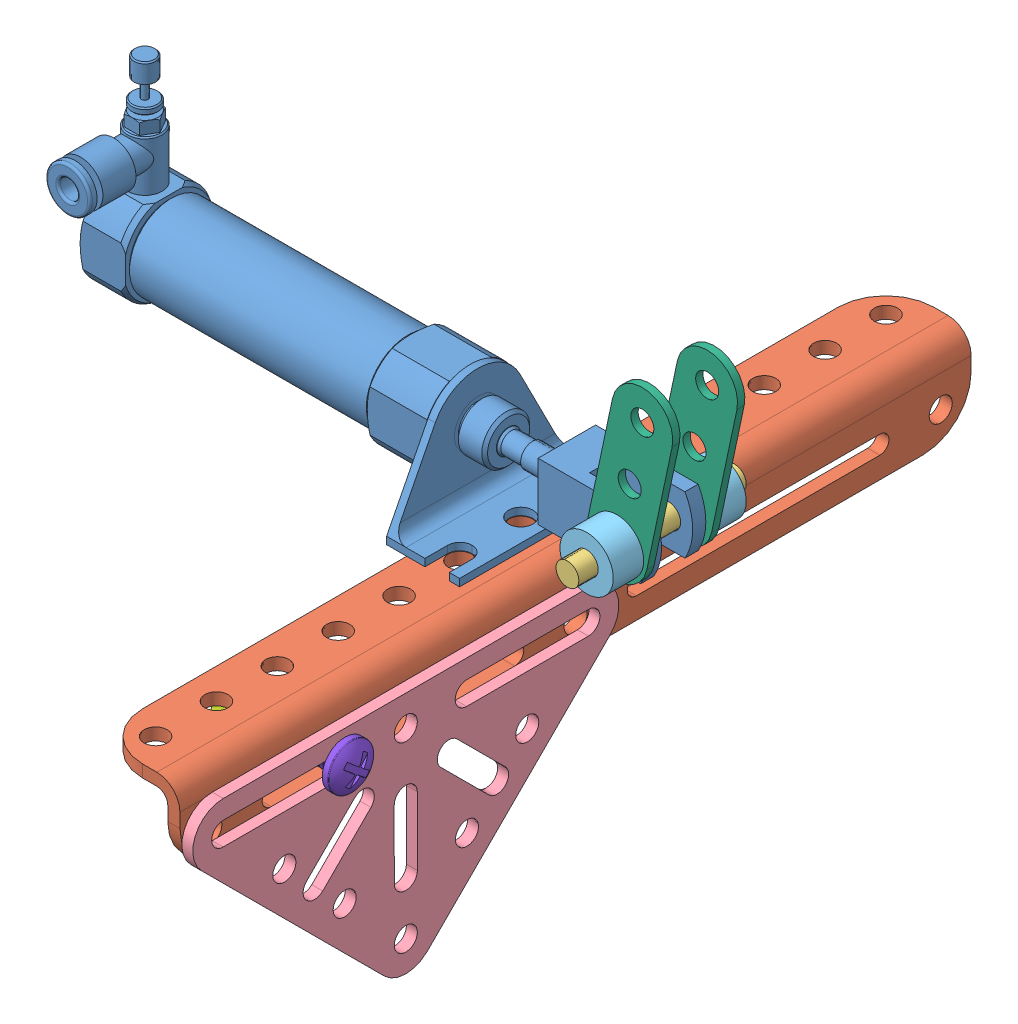
SolidWorks assembly Assem1, configuration Default. Lengths in mm.
Overall size (123.51 101.67 165.1).
10 component instances, 8 part files, 25 mates.
Components (placement in the parent):
- AirCylinder PART-3: AirCylinder PART [Default] at origin size (115.7 46.02 34.92)
- 13 Hole Angle-3: 13 Hole Angle [Default] at (41.891 -13.97 0) x (0 0 -1) z (-1 0 0) size (165.1 17.78 17.78)
- Axle-2: Axle [Default] at (75.85 0 0.4115) x (0.972535 -0.232757 0) z (0 0 1) size (4.78 4.78 34.92)
- TRIANGLE-2: TRIANGLE [Default] at (61.957 -24.888 37.7034) x (0 0 -1) z (-1 0 0) size (88.9 50.75 2.29)
- SHAFT-COLLAR-2: SHAFT-COLLAR [Default] at (75.85 0 -10.699) x (0.999484 0.03213 0) z (0 0 1) size (11.11 11.11 6.35)
- FLATBAR-3HOLE-3: FLATBAR-3HOLE [3HOLE] at (78.4905 12.4225 6) x (-0.207912 -0.978148 0) z (0 0 1) size (38.1 12.7 1.52)
- FLATBAR-3HOLE-4: FLATBAR-3HOLE [3HOLE] at (78.4905 12.4225 -7.524) x (0.207912 0.978148 0) z (0 0 1) size (38.1 12.7 1.52)
- SHAFT-COLLAR-3: SHAFT-COLLAR [Default] at (75.85 0 10.699) size (11.11 11.11 6.35)
- HEXSTANDOFF-2: HEXSTANDOFF [Default] at (57.131 -24.888 50.4034) x (0 0.02435 0.999703) z (0 -0.999703 0.02435) size (9.18 18.67 7.95)
- Screw-3: Screw [Default] at (52.432 -24.888 50.4034) x (0 -0.779296 0.626656) z (0 0.626656 0.779296) size (9.47 13.4 9.47)
Mates (geometry in assembly coordinates):
- Coincident2: coordinate: point of AirCylinder PART-3; point of assembly
- Concentric1: concentric: cylinder of AirCylinder PART-3 through (48.241 -13.97 0) axis (0 1 0) radius 2.54; cylinder of 13 Hole Angle-3 through (48.241 -13.97 0) axis (0 -1 0) radius 2.413
- Coincident3: coincident: plane of AirCylinder PART-3 through (39.224 -13.97 17.4625) normal (0 -1 0); plane of 13 Hole Angle-3 through (41.891 -13.97 -82.55) normal (0 1 0)
- Concentric2: concentric: circle of AirCylinder PART-3; circle of 13 Hole Angle-3
- Coincident9: coincident: plane of 13 Hole Angle-3 through (59.671 -18.796 -82.55) normal (1 0 0); plane of TRIANGLE-2 through (59.671 -24.888 75.8189) normal (-1 0 0)
- Coincident12: coincident: plane of 13 Hole Angle-3 through (41.891 -27.301 63.5) normal (0 1 0); plane of TRIANGLE-2 through (61.957 -27.301 75.8189) normal (0 1 0)
- Parallel7: parallel: plane of 13 Hole Angle-3 through (41.891 -27.301 63.5) normal (0 1 0); plane of TRIANGLE-2 through (61.957 -27.301 75.8189) normal (0 1 0)
- Concentric5: concentric: circle of AirCylinder PART-3; cylinder of Axle-2 through (75.85 0 17.874) axis (0 0 -1) radius 2.3876
- Concentric6: concentric: cylinder of Axle-2 through (75.85 0 17.874) axis (0 0 -1) radius 2.3876; circle of FLATBAR-3HOLE-3
- Coincident15: coincident: plane of AirCylinder PART-3 through (68.85 0 6) normal (0 0 1); plane of FLATBAR-3HOLE-3 through (81.131 24.8449 6) normal (0 0 -1)
- Coincident16: coincident: plane of AirCylinder PART-3 through (68.85 0 -6) normal (0 0 -1); plane of FLATBAR-3HOLE-4 through (75.85 0 -6) normal (0 0 1)
- Concentric7: concentric: cylinder of Axle-2 through (75.85 0 17.874) axis (0 0 -1) radius 2.3876; cylinder of FLATBAR-3HOLE-4 through (75.85 0 -7.524) axis (0 0 1) radius 2.413
- Concentric8: concentric: cylinder of Axle-2 through (75.85 0 17.874) axis (0 0 -1) radius 2.3876; cylinder of SHAFT-COLLAR-3 through (75.85 0 7.524) axis (0 0 1) radius 2.413
- Concentric9: concentric: cylinder of Axle-2 through (75.85 0 17.874) axis (0 0 -1) radius 2.3876; cylinder of SHAFT-COLLAR-2 through (75.85 0 -13.874) axis (0 0 1) radius 2.413
- Coincident17: coincident: plane of SHAFT-COLLAR-2 through (75.85 0 -7.524) normal (0 0 1); plane of FLATBAR-3HOLE-4 through (75.85 0 -7.524) normal (0 0 -1)
- Coincident18: coincident: plane of FLATBAR-3HOLE-3 through (81.131 24.8449 7.524) normal (0 0 1); plane of SHAFT-COLLAR-3 through (75.85 0 7.524) normal (0 0 -1)
- Distance3: distance = 4 mm: plane of Axle-2 through (75.85 0 17.874) normal (0 0 1); plane of SHAFT-COLLAR-3 through (75.85 0 13.874) normal (0 0 1)
- Parallel8: parallel: plane of FLATBAR-3HOLE-3 through (74.9197 26.1652 7.524) normal (-0.978148 0.207912 0); plane of FLATBAR-3HOLE-4 through (69.6388 1.3202 -6) normal (-0.978148 0.207912 0)
- Angle1: planar angle = 1.361357 rad: line of FLATBAR-3HOLE-3 through (74.9197 26.1652 7.524) axis (-0.207912 -0.978148 0); line of AirCylinder PART-3 through (79.2423 6 6) axis (-1 0 0)
- Coincident35: coincident: plane of 13 Hole Angle-3 through (57.131 -18.796 -82.55) normal (-1 0 0); plane of HEXSTANDOFF-2 through (57.131 -24.888 50.4189) normal (1 0 0)
- Concentric19: concentric: circle of TRIANGLE-2; cylinder of HEXSTANDOFF-2 through (38.462 -24.888 50.4189) axis (-1 0 0) radius 1.8986
- Concentric20: concentric: cylinder of TRIANGLE-2 through (61.957 -24.888 50.4189) axis (-1 0 0) radius 2.413; circle of HEXSTANDOFF-2
- Coincident40: coincident: plane of TRIANGLE-2 through (61.957 -24.888 75.8189) normal (1 0 0); plane of Screw-3 through (61.957 -28.5796 53.3874) normal (-1 0 0)
- Concentric21: concentric: cylinder of HEXSTANDOFF-2 through (38.462 -24.888 50.4189) axis (-1 0 0) radius 1.8986; circle of Screw-3
- Distance7: distance = 8 mm: cylinder of TRIANGLE-2 through (61.957 -24.888 25.0034) axis (-1 0 0) radius 2.413; cylinder of 13 Hole Angle-3 through (41.891 -25.4 12.7) axis (1 0 0) radius 1.901
